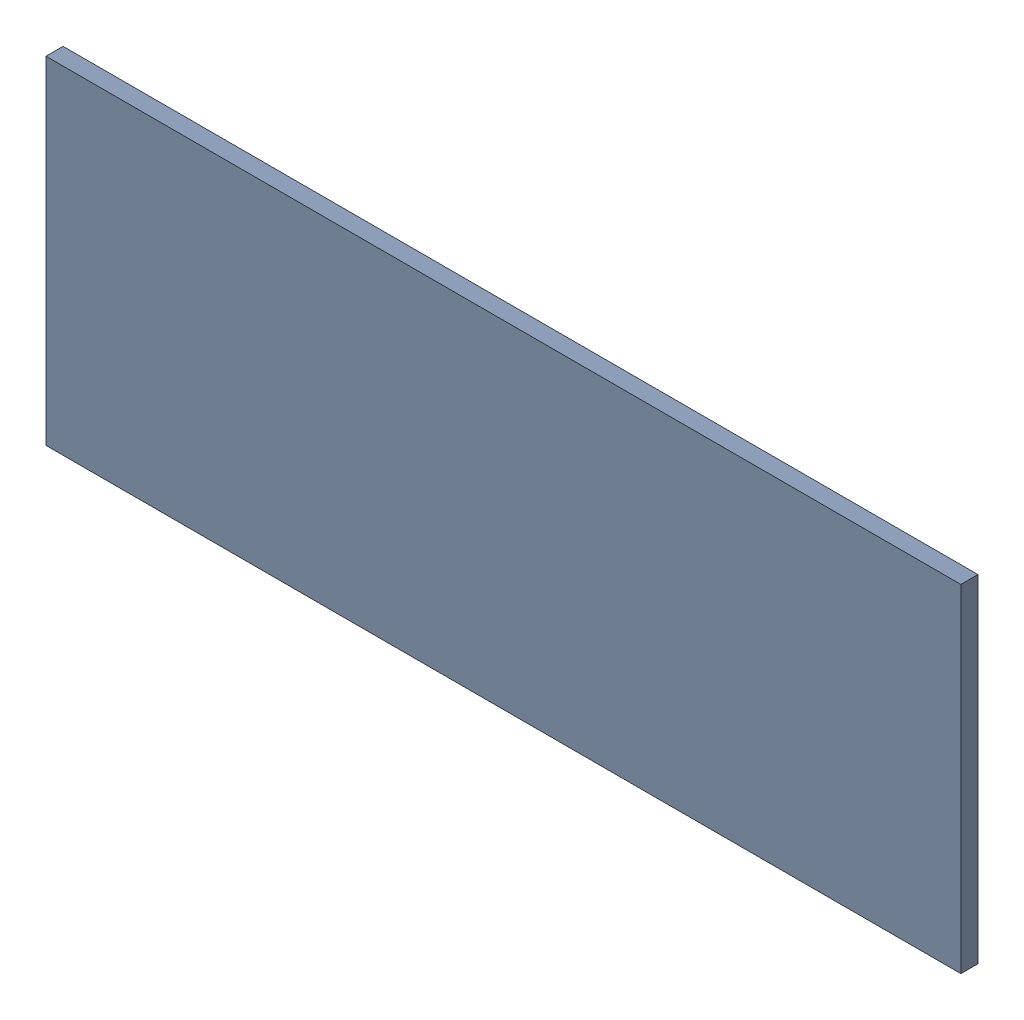
SolidWorks assembly Pad RAK4600-30(29.2mm,22.5mm) on Top Layer, configuration Predeterminado. Lengths in mm.
Overall size (1.9 0.7 0.04).
2 component instances, 1 part files, 0 mates.
Components (placement in the parent):
- Pad RAK4600-30(29.2mm,22.5mm) on Top Layer-1-1: Pad RAK4600-30(29.2mm,22.5mm) on Top Layer-1 [Predeterminado] at (-68.317 -44.187 -0.0457) size (1.9 0.7 0.04)
  - Pad RAK4600-30(29.2mm,22.5mm) on Top Layer-Part-1-1: Pad RAK4600-30(29.2mm,22.5mm) on Top Layer-Part-1 [Predeterminado] at origin size (1.9 0.7 0.04)
